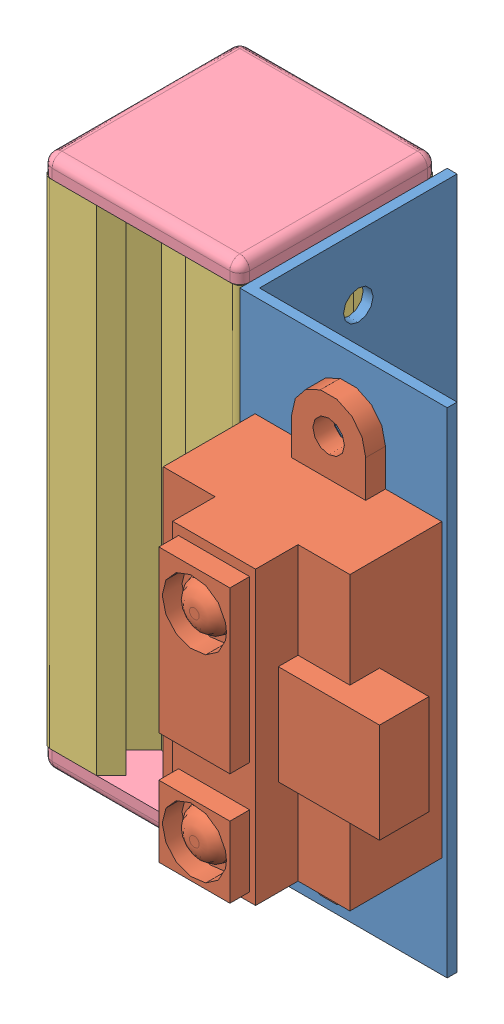
SolidWorks assembly capteur_front, configuration Default. Lengths in mm.
Overall size (45.45 54 36.6).
5 component instances, 4 part files, 12 mates.
Components (placement in the parent):
- corniere_angle90_H50_l20-1: corniere_angle90_H50_l20 [Default] at (-9.9399 -26.4449 4.3922) size (21 50 21)
- GP2D12-1: GP2D12 [Default] at (10.5101 -16.1949 4.3922) x (0 1 0) z (1 0 0) size (44.5 15.6 23.9)
- Profilé Aluminium Rexroth 20x20 L50-1: Profilé Aluminium Rexroth 20x20 L50 [Default] at (-19.9399 -26.4449 -5.6078) size (20 50 20)
- bouchonXD_Rexroth_20x20-1: bouchonXD_Rexroth_20x20 [Default] at (-29.9399 23.5551 4.3922) x (1 0 0) z (0 1 0) size (20 20 2)
- bouchonXD_Rexroth_20x20-2: bouchonXD_Rexroth_20x20 [Default] at (-29.9399 -26.4449 -15.6078) x (1 0 0) z (0 -1 0) size (20 20 2)
Mates (geometry in assembly coordinates):
- Coïncidente1: coincident anti-aligned: plane of corniere_angle90_H50_l20-1 through (11.0601 23.5551 4.3922) normal (0 0 1); plane of GP2D12-1 through (-8.3899 -16.1949 4.3922) normal (0 0 -1)
- Coaxiale1: concentric aligned: cylinder of corniere_angle90_H50_l20-1; cylinder of GP2D12-1
- Coaxiale2: concentric aligned: cylinder of corniere_angle90_H50_l20-1; cylinder of GP2D12-1
- Coïncidente2: coincident aligned: plane of corniere_angle90_H50_l20-1 through (11.0601 23.5551 4.3922) normal (0 0 1); plane of Profilé Aluminium Rexroth 20x20 L50-1 through (-15.4399 23.5551 4.3922) normal (0 0 1)
- Coïncidente3: coincident aligned: plane of corniere_angle90_H50_l20-1 through (-9.9399 23.5551 4.3922) normal (0 1 0); plane of Profilé Aluminium Rexroth 20x20 L50-1 through (-19.9399 23.5551 -9.6078) normal (0 1 0)
- Coïncidente4: coincident anti-aligned: plane of corniere_angle90_H50_l20-1 through (-9.9399 23.5551 4.3922) normal (-1 0 0); plane of Profilé Aluminium Rexroth 20x20 L50-1 through (-9.9399 23.5551 -10.1078) normal (1 0 0)
- Coïncidente5: coincident anti-aligned: plane of Profilé Aluminium Rexroth 20x20 L50-1 through (-19.9399 23.5551 -9.6078) normal (0 1 0); plane of bouchonXD_Rexroth_20x20-1 through (-29.9399 23.5551 -15.6078) normal (0 -1 0)
- Coïncidente6: coincident aligned: plane of Profilé Aluminium Rexroth 20x20 L50-1 through (-15.4399 23.5551 -15.6078) normal (0 0 -1); plane of bouchonXD_Rexroth_20x20-1 through (-29.9399 25.5551 -15.6078) normal (0 0 -1)
- Coïncidente7: coincident aligned: plane of Profilé Aluminium Rexroth 20x20 L50-1 through (-29.9399 23.5551 -1.1078) normal (-1 0 0); plane of bouchonXD_Rexroth_20x20-1 through (-29.9399 25.5551 4.3922) normal (-1 0 0)
- Coïncidente8: coincident anti-aligned: plane of Profilé Aluminium Rexroth 20x20 L50-1 through (-19.9399 -26.4449 -9.6078) normal (0 -1 0); plane of bouchonXD_Rexroth_20x20-2 through (-29.9399 -26.4449 4.3922) normal (0 1 0)
- Coïncidente9: coincident aligned: plane of Profilé Aluminium Rexroth 20x20 L50-1 through (-24.4399 23.5551 -15.6078) normal (0 0 -1); plane of bouchonXD_Rexroth_20x20-2 through (-29.9399 -28.4449 -15.6078) normal (0 0 -1)
- Coïncidente10: coincident aligned: plane of Profilé Aluminium Rexroth 20x20 L50-1 through (-29.9399 23.5551 -10.1078) normal (-1 0 0); plane of bouchonXD_Rexroth_20x20-2 through (-29.9399 -28.4449 -15.6078) normal (-1 0 0)
